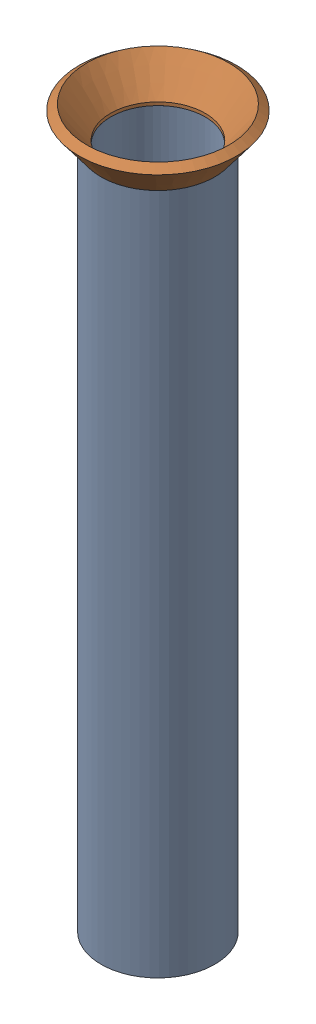
SolidWorks assembly Pipe 11, configuration Default. Lengths in mm.
Overall size (19.33 80.09 19.33).
2 component instances, 2 part files, 0 mates.
Components (placement in the parent):
- Pipe 11-1: Pipe 11 [Default<As Machined>] at (-295.8179 610.8803 264.0835) size (12.7 76.2 12.7)
- Flared pipe end - .5 inch-1: Flared pipe end - .5 inch [Default<As Machined>] at (-964.8447 -137.8618 264.0835) x (0.994549 0 0.104268) z (0 1 0) size (17.59 17.59 3.89)
